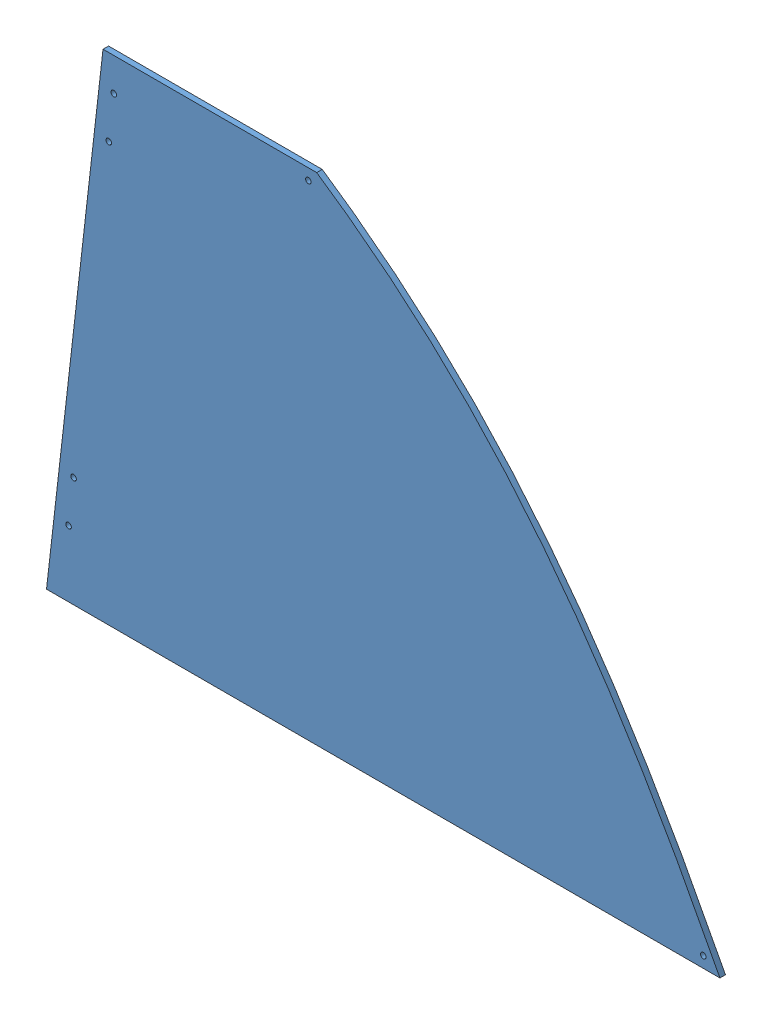
SolidWorks assembly GE-19080-Right-Red, configuration Default. Lengths in mm.
Overall size (771.1 567.83 44.58).
2 component instances, 2 part files, 3 mates.
Components (placement in the parent):
- GE-19080-1: GE-19080 [GE-19080] at origin size (771.1 567.83 6.35)
- GE-19080-Right-Red-Vinyl-1: GE-19080-Right-Red-Vinyl [Notched] at (0 0 6.35) size (771.1 567.83 0.13)
Mates (geometry in assembly coordinates):
- Coincident1: coincident: plane of assembly; plane of assembly; plane of GE-19080-1 through (546.1766 314.686 6.35) normal (0 0 1); plane of GE-19080-Right-Red-Vinyl-1 through (546.1766 314.686 6.35) normal (0 0 -1)
- Coincident2: coincident: plane of assembly; plane of assembly; plane of GE-19080-1 through (32.7402 567.8263 582.3432) normal (-0.993572 0.113203 0); plane of GE-19080-Right-Red-Vinyl-1 through (32.7402 567.8263 582.4702) normal (-0.993572 0.113203 0)
- Coincident3: coincident: plane of assembly; plane of assembly; plane of GE-19080-1 through (0 0 6.35) normal (0 -1 0); plane of GE-19080-Right-Red-Vinyl-1 through (0 0 6.477) normal (0 -1 0)
